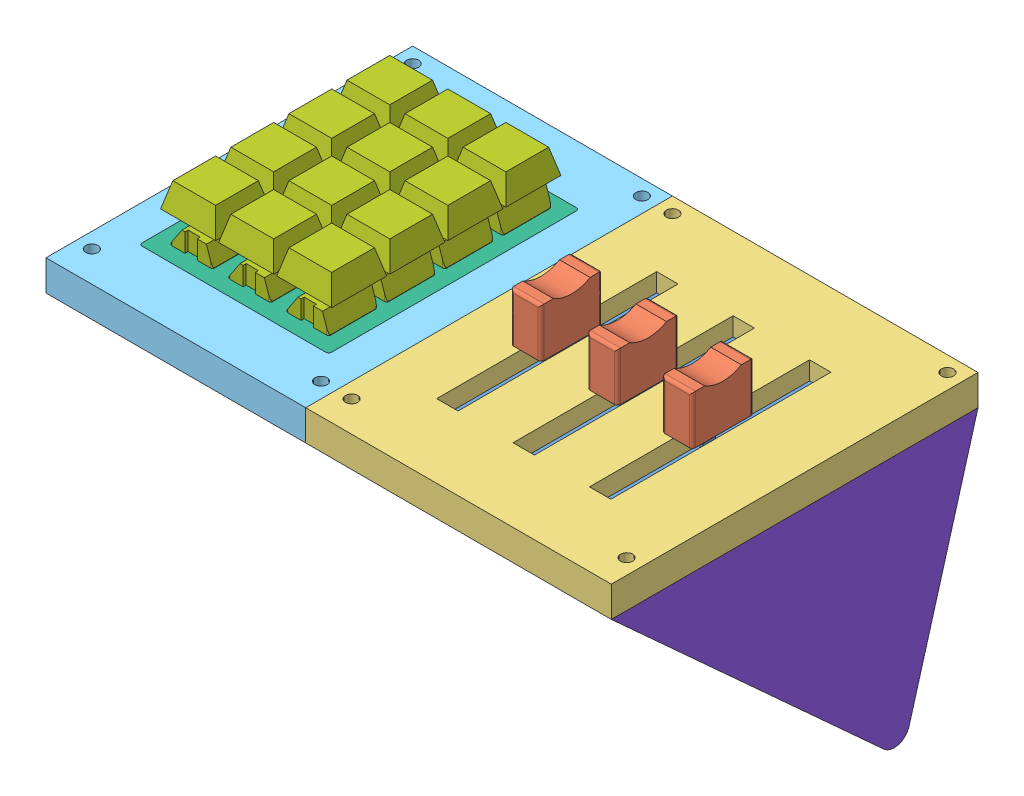
SolidWorks assembly AssemblageFinale, configuration Default. Lengths in mm.
Overall size (185 110.7 120).
35 component instances, 9 part files, 9 mates.
Components (placement in the parent):
- assemPotentiomètreParoi-1: assemPotentiomètreParoi [Default] at (37.9628 66.8707 92.8282) size (100 35 120)
  - Assempotentiomètre-1: Assempotentiomètre [Default] at (34.4057 37.7849 55.1064) size (10 35 75)
    - potentiometre-1: potentiometre [Default] at (21.4554 37.7055 61.994) size (9 26 75)
    - capuchon_potentiomètre-1: capuchon_potentiomètre [Default] at (21.4554 51.7055 62.0657) size (10 16 20)
  - parroiPotentiomètre-2: parroiPotentiomètre [Default] at (58.2573 87.4904 116.6213) x (1 0 0) z (0 0 -1) size (100 10 120)
  - Assempotentiomètre-2: Assempotentiomètre [Default] at (58.9057 37.7849 55.1064) size (10 35 75)
    - potentiometre-1: potentiometre [Default] at (21.4554 37.7055 61.994) size (9 26 75)
    - capuchon_potentiomètre-1: capuchon_potentiomètre [Default] at (21.4554 51.7055 62.0657) size (10 16 20)
  - Assempotentiomètre-3: Assempotentiomètre [Default] at (9.4057 37.7849 55.1064) size (10 35 75)
    - potentiometre-1: potentiometre [Default] at (21.4554 37.7055 61.994) size (9 26 75)
    - capuchon_potentiomètre-1: capuchon_potentiomètre [Default] at (21.4554 51.7055 62.0657) size (10 16 20)
  - accrochePotentiometre-1: accrochePotentiometre [Default] at (18.6111 71.4904 138.7565) size (24 10 15)
  - accrochePotentiometre-2: accrochePotentiometre [Default] at (18.6111 71.4904 110.7271) size (24 10 15)
  - accrochePotentiometre-3: accrochePotentiometre [Default] at (43.6111 71.4904 138.7565) size (24 10 15)
  - accrochePotentiometre-4: accrochePotentiometre [Default] at (43.6111 71.4904 110.8747) size (24 10 15)
  - accrochePotentiometre-5: accrochePotentiometre [Default] at (68.6111 71.4904 138.7565) size (24 10 15)
  - accrochePotentiometre-6: accrochePotentiometre [Default] at (68.6111 71.4904 110.8747) size (24 10 15)
- assemblageAccrocheKeyboard-1: assemblageAccrocheKeyboard [Default] at (-43.1491 87.0816 114.805) size (85 27.6 120)
  - accrocheKeyboard-1: accrocheKeyboard [Default] at (46.8691 57.2795 94.6446) size (85 10 120)
  - keyboard-1: keyboard [Default] at (2.8102 -5.5564 65.468) size (62 27.6 82)
    - plaque clavier-1: plaque clavier [Default] at (44.0589 62.8359 29.1766) size (62 10 82)
    - key-1: key [Default] at (25.0589 67.9359 57.1766) size (18 22.5 18)
    - key-2: key [Default] at (44.0589 67.9359 57.1766) size (18 22.5 18)
    - key-3: key [Default] at (63.0589 67.9359 57.1766) size (18 22.5 18)
    - key-4: key [Default] at (25.0589 67.9359 38.1766) size (18 22.5 18)
    - key-5: key [Default] at (44.0589 67.9359 38.1766) size (18 22.5 18)
    - key-6: key [Default] at (63.0589 67.9359 38.1766) size (18 22.5 18)
    - key-7: key [Default] at (25.0589 67.9359 19.1766) size (18 22.5 18)
    - key-8: key [Default] at (44.0589 67.9359 19.1766) size (18 22.5 18)
    - key-9: key [Default] at (63.0589 67.9359 19.1766) size (18 22.5 18)
    - key-10: key [Default] at (44.0589 67.9359 0.1766) size (18 22.5 18)
    - key-11: key [Default] at (25.0589 67.9359 0.1766) size (18 22.5 18)
    - key-12: key [Default] at (63.0589 67.9359 0.1766) size (18 22.5 18)
- boitier-3: boitier [Default] at (53.7201 144.3611 209.4495) x (-1 0 0) z (0 0 -1) size (185 82.7 120)
- Arduino Pro Micro USB Type C.step-1: Arduino Pro Micro USB Type C.step [Default] at (62.6101 111.7327 172.436) x (0 0.274679 0.961536) z (0 0.961536 -0.274679) size (36.2 18.3 4.66)
Mates (geometry in assembly coordinates):
- Coincident1: coincident anti-aligned: plane of assemPotentiomètreParoi-1/parroiPotentiomètre-2 through (46.2201 144.3611 149.4495) normal (-1 0 0); plane of assemblageAccrocheKeyboard-1/accrocheKeyboard-1 through (46.2201 154.3611 269.4495) normal (1 0 0)
- Coincident2: coincident aligned: plane of assemPotentiomètreParoi-1/parroiPotentiomètre-2 through (96.2201 154.3611 209.4495) normal (0 1 0); plane of assemblageAccrocheKeyboard-1/accrocheKeyboard-1 through (3.7201 154.3611 209.4495) normal (0 1 0)
- Coincident3: coincident aligned: plane of assemPotentiomètreParoi-1/parroiPotentiomètre-2 through (46.2201 144.3611 149.4495) normal (0 0 -1); plane of assemblageAccrocheKeyboard-1/accrocheKeyboard-1 through (-38.7799 154.3611 149.4495) normal (0 0 -1)
- Coincident12: coincident: plane of assemPotentiomètreParoi-1/parroiPotentiomètre-2 through (96.2201 144.3611 209.4495) normal (0 -1 0); plane of boitier-3 through (-154.3176 144.3611 149.4495) normal (0 1 0)
- Coincident14: coincident: line of assemblageAccrocheKeyboard-1/accrocheKeyboard-1 through (46.2201 144.3611 149.4495) axis (-1 0 0); line of boitier-3 through (145.6824 144.3611 149.4495) axis (-1 0 0)
- Coincident15: coincident aligned: plane of assemblageAccrocheKeyboard-1/accrocheKeyboard-1 through (-38.7799 154.3611 269.4495) normal (-1 0 0); plane of boitier-3 through (-38.7799 154.3611 149.4495) normal (-1 0 0)
- Coincident16: coincident: plane of boitier-3 through (44.5701 111.3096 172.4113) normal (1 0 0); plane of Arduino Pro Micro USB Type C.step-1 through (44.5701 112.2246 168.3331) normal (-1 0 0)
- Coincident17: coincident: plane of boitier-3 through (58.1901 116.2711 170.9939) normal (0 -0.961536 0.274679); plane of Arduino Pro Micro USB Type C.step-1 through (56.9401 116.3503 171.2712) normal (0 0.961536 -0.274679)
- Coincident18: coincident anti-aligned: plane of boitier-3 through (53.7201 130.6815 161.563) normal (0 0.274679 0.961536); plane of Arduino Pro Micro USB Type C.step-1 through (62.6101 111.8291 166.9485) normal (0 -0.274679 -0.961536)
